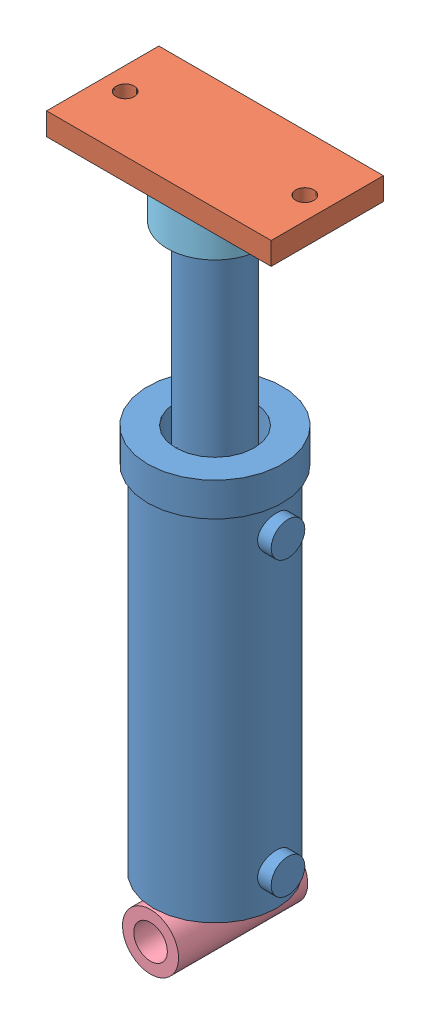
SolidWorks assembly 01-039-00-0, configuration Default. Lengths in mm.
Overall size (254 782.51 152.4).
6 component instances, 6 part files, 14 mates.
Components (placement in the parent):
- PMC-21012-1: PMC-21012 [Default] at origin size (158.75 752.48 152.4)
- 01-035-00-0-1: 01-035-00-0 [Default] at (-127 688.975 63.5) size (254 25.4 127)
- hex nut_ai-1: hex nut_ai [HNUT 0.7500-10-D-C] at (-112.7125 672.084 -55.2511) x (1 0 0) z (0 -1 0) size (28.57 33 16.89)
- Base Cross Post-1: Base Cross Post [Default] at (-0.3461 -31.75 -73.4983) x (-0.160376 -0.987056 0) z (0 0 1) size (63.42 63.42 146.05)
- Press Foot Collar-1: Press Foot Collar [Default] at (0 638.175 0) x (0 0 -1) z (1 0 0) size (111.76 108.7 111.76)
- Press Foot Pin-1: Press Foot Pin [Default] at (-64.5385 663.575 0) x (1 0 0) z (0 -0.003027 0.999995) size (127 19.05 19.05)
Mates (geometry in assembly coordinates):
- Tangent1: tangent: cylinder of PMC-21012-1 through (50.8 850.9 0) axis (-1 0 0) radius 31.75; plane of 01-035-00-0-1 through (-127 882.65 -50.8) normal (0 1 0)
- Parallel1: parallel anti-aligned: plane of PMC-21012-1 through (0 438.15 0) normal (0 1 0); plane of 01-035-00-0-1 through (-127 688.975 -63.5) normal (0 -1 0)
- Distance2: distance = 3.175 mm: plane of 01-035-00-0-1 through (-53.975 882.65 34.925) normal (0 0 -1); cylinder of PMC-21012-1 through (50.8 850.9 0) axis (-1 0 0) radius 31.75
- Coincident71: coincident anti-aligned: plane of 01-035-00-0-1 through (-127 688.975 -63.5) normal (0 -1 0); plane of hex nut_ai-1 through (-112.7125 688.975 -38.7533) normal (0 1 0)
- Coincident10: coincident aligned: plane of 01-035-00-0-1 through (-127 714.375 63.5) normal (-1 0 0); plane of hex nut_ai-1 through (-127 688.975 -47.0022) normal (-1 0 0)
- Coincident11: coincident: plane of 01-035-00-0-1 through (-127 714.375 -63.5) normal (0 0 -1); line of hex nut_ai-1 through (-127 687.07 -63.5) axis (0 -1 0)
- Coincident72: coincident: moEndPointRef_w of 01-035-00-0-1; plane of assembly
- Perpendicular1: perpendicular: plane of PMC-21012-1 through (82.55 38.1 0) normal (1 0 0); plane of Base Cross Post-1 through (-0.3461 -31.75 -73.4983) normal (0 0 -1)
- Concentric3: concentric anti-aligned: circle of PMC-21012-1; cylinder of Base Cross Post-1 through (-0.3461 -31.75 72.5517) axis (0 0 -1) radius 31.7101
- Coincident75: coincident anti-aligned: plane of PMC-21012-1 through (0 688.975 0) normal (0 1 0); plane of 01-035-00-0-1 through (-127 688.975 -63.5) normal (0 -1 0)
- Concentric8: concentric anti-aligned: cylinder of PMC-21012-1 through (0 688.975 0) axis (0 -1 0) radius 34.925; cylinder of Press Foot Collar-1 through (0 638.175 0) axis (0 1 0) radius 34.925
- Concentric9: concentric aligned: cylinder of PMC-21012-1 through (-76.2 663.575 0) axis (1 0 0) radius 9.525; cylinder of Press Foot Collar-1 through (-53.975 663.575 0) axis (1 0 0) radius 9.525
- Concentric10: concentric anti-aligned: cylinder of Press Foot Collar-1 through (-53.975 663.575 0) axis (1 0 0) radius 9.525; cylinder of Press Foot Pin-1 through (62.4615 663.575 0) axis (-1 0 0) radius 9.525
- Distance3: distance = 9.525 mm aligned: plane of 01-035-00-0-1 through (-127 714.375 -63.5) normal (0 0 -1); cylinder of Press Foot Collar-1 through (0 688.975 0) axis (0 -1 0) radius 53.975
